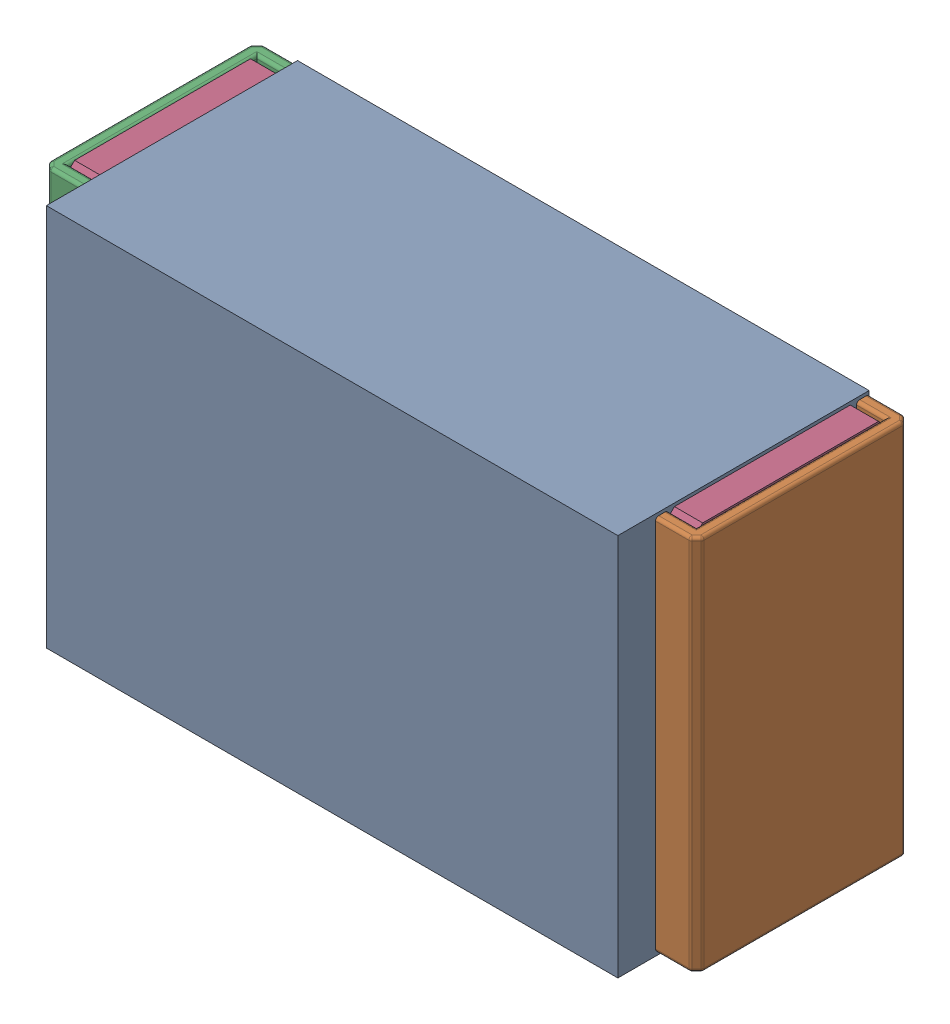
SolidWorks assembly R12, configuration Default. Lengths in mm.
Overall size (1.04 0.61 0.4).
3 component instances, 2 part files, 0 mates.
Components (placement in the parent):
- 1088880352-1: 1088880352 [Default] at (3.975 33.85 0) size (0.91 0.61 0.4)
  - Extruded-28-1: Extruded-28 [Default] at origin size (0.91 0.61 0.4)
- R0402-1: R0402 [Default] at (3.9751 33.85 0) x (1 0 0) z (0 -1 0) size (1.04 0.34 0.6)
